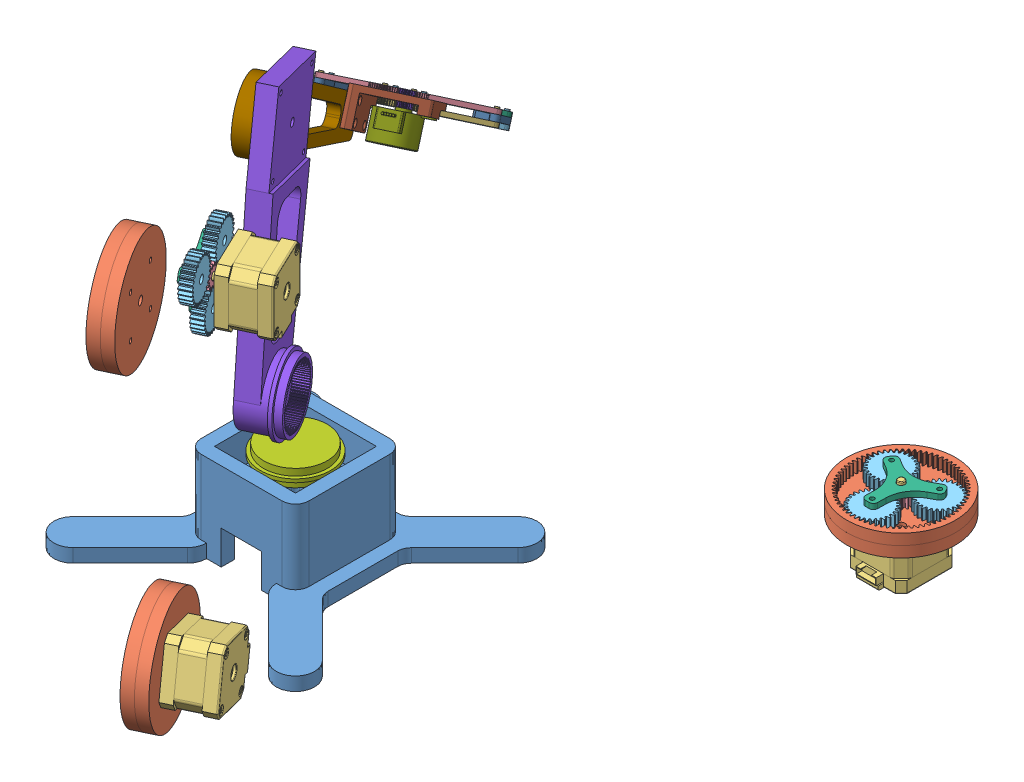
SolidWorks assembly all, configuration Default. Lengths in mm.
Overall size (284.8 287.34 362.45).
43 component instances, 17 part files, 13 mates.
Components (placement in the parent):
- base-1: base [Default] at (133.4042 7.7689 -91.0413) size (355.59 82.04 366.94)
  - base-1: base [Default] at (-39.9804 267.798 169.9634) x (-1 0 0) z (0 0 1) size (193.14 65 193.14)
  - assembly-2: assembly [Default] at (4.2927 267.598 114.0274) size (80.55 55.32 81.33)
    - body-1: body [Default] at (-23.904 -48.692 -2.8474) size (80.55 16 80.55)
    - nema17new-1: nema17new [Default] at (218.7474 -56.692 -230.094) size (42 55.32 47)
    - Metric - Spur gear 1M 14T 20PA 8FW ---S14N75H50L5N-1: Metric - Spur gear 1M 14T 20PA 8FW ---S14N75H50L5N [Metric - Spur gear 1M 14T 20PA 8FW ---S14N75H50L5N] at (218.7474 -32.692 -230.094) x (0 -1 0) z (0.831939 0 -0.554867) size (8 15.69 16)
    - Metric - Spur gear 1M 28T 20PA 8FW ---S28N75H50L0.8N-1: Metric - Spur gear 1M 28T 20PA 8FW ---S28N75H50L0.8N [Metric - Spur gear 1M 28T 20PA 8FW ---S28N75H50L0.8N] at (200.7746 -40.692 -240.9557) x (0 1 0) z (0.979313 0 0.202352) size (8 29.87 29.87)
    - Metric - Spur gear 1M 28T 20PA 8FW ---S28N75H50L0.8N-2: Metric - Spur gear 1M 28T 20PA 8FW ---S28N75H50L0.8N [Metric - Spur gear 1M 28T 20PA 8FW ---S28N75H50L0.8N] at (218.3274 -40.692 -209.0982) x (0 1 0) z (0.893341 0 -0.449379) size (8 29.87 29.87)
    - Metric - Spur gear 1M 28T 20PA 8FW ---S28N75H50L0.8N-4: Metric - Spur gear 1M 28T 20PA 8FW ---S28N75H50L0.8N [Metric - Spur gear 1M 28T 20PA 8FW ---S28N75H50L0.8N] at (237.1404 -40.692 -240.2282) x (0 1 0) z (0.977458 0 0.21113) size (8 29.87 29.87)
    - outputFrame-1: outputFrame [Default] at (-568.7411 -32.692 -389.7012) x (-0.855852 0 -0.517221) z (0.517221 0 -0.855852) size (39.62 4 44.76)
- 40mmPitch80TeethRingTurret-1: 40mmPitch80TeethRingTurret [Default] at (163.1487 265.5669 6.9469) x (0.877834 0 -0.478965) z (0.478965 0 0.877834) size (52 12.5 52)
- assembly-1: assembly [Default] at (129.8849 308.0669 26.7001) x (0.429376 0 0.903126) z (0 -1 0) size (80.55 55.32 81.33) (flexible)
  - body-1: body [Default] at (3.5356 -10 1.8024) size (80.55 16 80.55)
  - nema17new-1: nema17new [Default] at (218.7474 -56.692 -230.094) size (42 55.32 47)
  - Metric - Spur gear 1M 14T 20PA 8FW ---S14N75H50L5N-1: Metric - Spur gear 1M 14T 20PA 8FW ---S14N75H50L5N [Metric - Spur gear 1M 14T 20PA 8FW ---S14N75H50L5N] at (218.7474 -32.692 -230.094) x (0 -1 0) z (0.831939 0 -0.554867) size (8 15.69 16)
  - Metric - Spur gear 1M 28T 20PA 8FW ---S28N75H50L0.8N-1: Metric - Spur gear 1M 28T 20PA 8FW ---S28N75H50L0.8N [Metric - Spur gear 1M 28T 20PA 8FW ---S28N75H50L0.8N] at (200.7746 -40.692 -240.9557) x (0 1 0) z (0.979313 0 0.202352) size (8 29.87 29.87)
  - Metric - Spur gear 1M 28T 20PA 8FW ---S28N75H50L0.8N-2: Metric - Spur gear 1M 28T 20PA 8FW ---S28N75H50L0.8N [Metric - Spur gear 1M 28T 20PA 8FW ---S28N75H50L0.8N] at (218.3274 -40.692 -209.0982) x (0 1 0) z (0.893341 0 -0.449379) size (8 29.87 29.87)
  - Metric - Spur gear 1M 28T 20PA 8FW ---S28N75H50L0.8N-4: Metric - Spur gear 1M 28T 20PA 8FW ---S28N75H50L0.8N [Metric - Spur gear 1M 28T 20PA 8FW ---S28N75H50L0.8N] at (237.1404 -40.692 -240.2282) x (0 1 0) z (0.977458 0 0.21113) size (8 29.87 29.87)
  - outputFrame-1: outputFrame [Default] at (-568.7411 -32.692 -389.7012) x (-0.855852 0 -0.517221) z (0.517221 0 -0.855852) size (39.62 4 44.76)
- 40mmPitch80TeethRingUpperArm-1: 40mmPitch80TeethRingUpperArm [Default] at (133.9315 335.9931 12.3879) x (-0.13434 0.949795 -0.282563) z (0.407819 0.312872 0.857785) size (210.52 29.8 72.62)
- 40mmPitch80TeethRingArm-1: 40mmPitch80TeethRingArm [Default] at (96.4418 438.4103 -19.8868) x (-0.342926 -0.601782 -0.721291) z (-0.258391 0.798661 -0.543484) size (206.06 20.5 52)
- assembly-2: assembly [Default] at (97.3992 457.9874 4.9509) x (0.11152 -0.965683 0.234564) z (-0.414641 -0.259725 -0.872133) size (80.55 55.32 81.33)
  - body-1: body [Default] at (-23.904 -48.692 -2.8474) size (80.55 16 80.55)
  - nema17new-1: nema17new [Default] at (218.7474 -56.692 -230.094) size (42 55.32 47)
  - Metric - Spur gear 1M 14T 20PA 8FW ---S14N75H50L5N-1: Metric - Spur gear 1M 14T 20PA 8FW ---S14N75H50L5N [Metric - Spur gear 1M 14T 20PA 8FW ---S14N75H50L5N] at (218.7474 -32.692 -230.094) x (0 -1 0) z (0.831939 0 -0.554867) size (8 15.69 16)
  - Metric - Spur gear 1M 28T 20PA 8FW ---S28N75H50L0.8N-1: Metric - Spur gear 1M 28T 20PA 8FW ---S28N75H50L0.8N [Metric - Spur gear 1M 28T 20PA 8FW ---S28N75H50L0.8N] at (200.7746 -40.692 -240.9557) x (0 1 0) z (0.979313 0 0.202352) size (8 29.87 29.87)
  - Metric - Spur gear 1M 28T 20PA 8FW ---S28N75H50L0.8N-2: Metric - Spur gear 1M 28T 20PA 8FW ---S28N75H50L0.8N [Metric - Spur gear 1M 28T 20PA 8FW ---S28N75H50L0.8N] at (218.3274 -40.692 -209.0982) x (0 1 0) z (0.893341 0 -0.449379) size (8 29.87 29.87)
  - Metric - Spur gear 1M 28T 20PA 8FW ---S28N75H50L0.8N-4: Metric - Spur gear 1M 28T 20PA 8FW ---S28N75H50L0.8N [Metric - Spur gear 1M 28T 20PA 8FW ---S28N75H50L0.8N] at (237.1404 -40.692 -240.2282) x (0 1 0) z (0.977458 0 0.21113) size (8 29.87 29.87)
  - outputFrame-1: outputFrame [Default] at (-568.7411 -32.692 -389.7012) x (-0.855852 0 -0.517221) z (0.517221 0 -0.855852) size (39.62 4 44.76)
- gripper-2: gripper [Default] at (-22.5342 220.9244 -113.5111) x (0.903126 0 -0.429376) z (0.322586 0.659972 0.67851) size (118.13 38 129.49)
  - gripperArm-1: gripperArm [Default] at (123.3964 114.1407 25.9782) x (-0.335039 0.064326 -0.940006) z (0.942204 0.022874 -0.334257) size (60.1 8 18.82)
  - gripperArm-2: gripperArm [Default] at (11.7041 118.1313 26.2513) x (0.335039 0.064326 -0.940006) z (-0.942204 0.022874 -0.334257) size (60.1 8 18.82)
  - centerPiece-1: centerPiece [Default] at (54.5748 107.8499 117.9056) x (0 -0.068272 0.997667) z (-1 0 0) size (79.61 24 41.6)
  - parallelArmGearedBottom-2: parallelArmGearedBottom [Default] at (73.8046 100.865 73.5046) x (-0.97635 -0.01476 0.215691) z (-0.216196 0.066657 -0.974072) size (55.49 11 20.93)
  - parallelArmGearedBottom-3: parallelArmGearedBottom [Default] at (61.8395 100.9461 72.3196) x (0.801845 -0.040795 0.596138) z (-0.597532 -0.054744 0.799974) size (55.49 11 20.93)
  - parallelArmGearedTop-1: parallelArmGearedTop [Default] at (54.208 119.9078 102.5087) x (-0.97635 -0.01476 0.215691) z (-0.216196 0.066657 -0.974072) size (55.49 3 20.93)
  - parallelArmGearedTop-3: parallelArmGearedTop [Default] at (95.5636 122.0966 70.5235) x (0.801845 -0.040795 0.596138) z (-0.597532 -0.054744 0.799974) size (55.49 3 20.93)
  - parallelArm-5: parallelArm [Default] at (125.8655 110.5052 35.1618) x (0.97635 0.01476 -0.215691) z (0.216196 -0.066657 0.974072) size (50 11 15.44)
  - parallelArm-6: parallelArm [Default] at (13.496 111.1409 25.8723) x (-0.801845 0.040795 -0.596138) z (0.597532 0.054744 -0.799974) size (50 11 15.44)
  - parallelArmTop-5: parallelArmTop [Default] at (128.3521 116.0095 34.6436) x (0.97635 0.01476 -0.215691) z (0.216196 -0.066657 0.974072) size (50 3 15.44)
  - parallelArmTop-6: parallelArmTop [Default] at (11.1949 116.6729 24.9497) x (-0.801845 0.040795 -0.596138) z (0.597532 0.054744 -0.799974) size (50 3 15.44)
  - Step - 28BYJ-48-1: Step - 28BYJ-48 [Varsayılan] at (75.5502 85.7028 91.4743) x (1 0 0) z (0 -0.068272 0.997667) size (42 28.9 33.48)
  - 8mmPitch16Teeth-1: 8mmPitch16Teeth [Default] at (79.2827 107.4665 79.5665) x (0.741518 0.045806 -0.669367) z (0.670933 -0.050625 0.739788) size (8.97 10 8.97)
Mates (geometry in assembly coordinates):
- Coincident1: coincident anti-aligned: plane of base-1/assembly-2/body-1 through (141.2325 270.5669 24.7884) normal (0 1 0); plane of 40mmPitch80TeethRingTurret-1 through (137.6969 270.5669 22.986) normal (0 -1 0)
- Concentric1: concentric anti-aligned: cylinder of base-1/assembly-2/body-1 through (137.6969 260.3669 22.986) axis (0 1 0) radius 23.7; cylinder of 40mmPitch80TeethRingTurret-1 through (137.6969 275.5669 22.986) axis (0 -1 0) radius 23.5
- ProfileCenter1: profile center anti-aligned: plane of 40mmPitch80TeethRingTurret-1 through (137.6969 278.0669 22.986) normal (0 1 0); plane of assembly-1/body-1 through (130.5505 278.0669 -6.8343) normal (0 -1 0)
- Coincident3: coincident anti-aligned: plane of assembly-1/body-1 through (135.738 306.2645 27.8322) normal (-0.903126 0 0.429376); plane of 40mmPitch80TeethRingUpperArm-1 through (134.2199 308.0669 24.6391) normal (0.903126 0 -0.429376)
- Concentric2: concentric anti-aligned: cylinder of assembly-1/body-1 through (143.4318 308.0669 20.2595) axis (-0.903126 0 0.429376) radius 23.7; cylinder of 40mmPitch80TeethRingUpperArm-1 through (129.7042 308.0669 26.786) axis (0.903126 0 -0.429376) radius 23.5
- Coincident6: coincident aligned: plane of 40mmPitch80TeethRingUpperArm-1 through (89.2788 401.5526 -47.0635) normal (-0.367331 -0.517805 -0.772623); plane of assembly-2/body-1 through (75.9389 452.8825 -75.1221) normal (-0.367331 -0.517805 -0.772623)
- Coincident11: coincident aligned: plane of 40mmPitch80TeethRingUpperArm-1 through (93.6288 442.7517 -37.9141) normal (0.903126 0 -0.429376); plane of assembly-2/body-1 through (93.6288 442.7517 -37.9141) normal (0.903126 0 -0.429376)
- Coincident12: coincident anti-aligned: plane of assembly-2/body-1 through (84.5409 438.7937 -33.2737) normal (-0.903126 0 0.429376); plane of 40mmPitch80TeethRingArm-1 through (84.4169 442.7517 -33.5345) normal (0.903126 0 -0.429376)
- Concentric6: concentric anti-aligned: cylinder of assembly-2/body-1 through (93.6288 442.7517 -37.9141) axis (-0.903126 0 0.429376) radius 23.7; cylinder of 40mmPitch80TeethRingArm-1 through (79.9013 442.7517 -31.3876) axis (0.903126 0 -0.429376) radius 23.5
- Coincident13: coincident anti-aligned: plane of 40mmPitch80TeethRingUpperArm-1 through (85.137 411.8822 -26.1975) normal (-0.222333 0.855499 -0.467643); plane of assembly-2/body-1 through (111.3187 432.6209 -0.7061) normal (0.222333 -0.855499 0.467643)
- Coincident18: coincident anti-aligned: plane of 40mmPitch80TeethRingArm-1 through (65.7863 430.8154 -55.2537) normal (0.903126 0 -0.429376); plane of gripper-2/centerPiece-1 through (1.0499 406.5518 -191.4168) normal (-0.903126 0 0.429376)
- Coincident21: coincident anti-aligned: plane of 40mmPitch80TeethRingArm-1; plane of gripper-2/centerPiece-1
- Coincident22: coincident aligned: plane of 40mmPitch80TeethRingArm-1; plane of gripper-2/centerPiece-1
